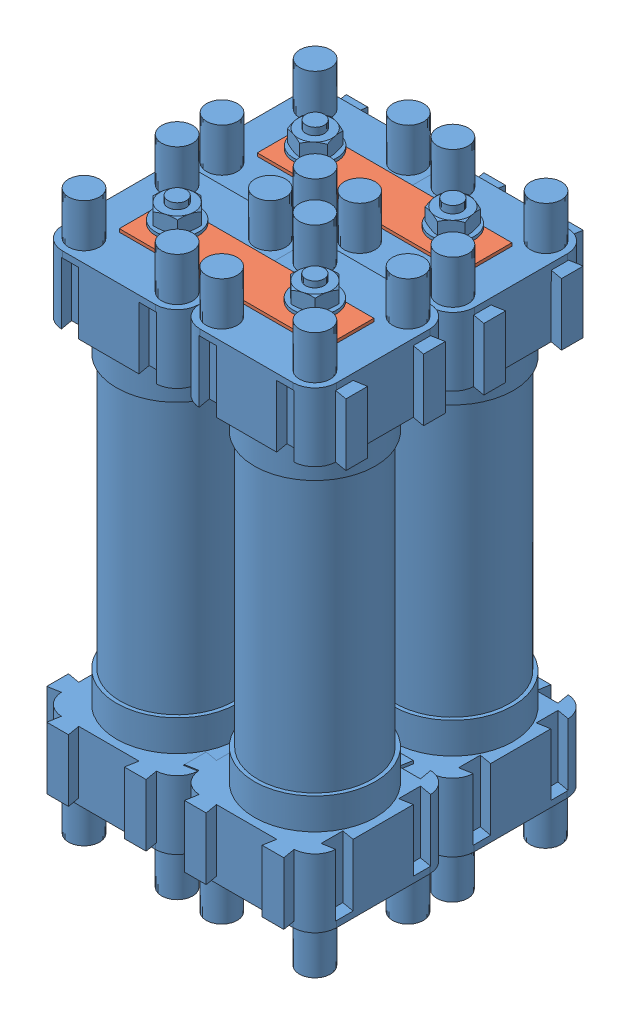
SolidWorks assembly Assem1, configuration Default. Lengths in mm.
Overall size (48.23 90.37 48.18).
7 component instances, 3 part files, 11 mates.
Components (placement in the parent):
- Cell w Caps-1: Cell w Caps [Default] at (52.4075 49.9991 53.4777) size (26 90 26)
- Cell w Caps-2: Cell w Caps [Default] at (74.4075 49.9991 53.2988) size (26 90 26)
- Cell w Caps-4: Cell w Caps [Default] at (74.5867 49.6475 31.2988) x (0 0 1) z (0.999999 -0.001067 0) size (26 90 26)
- Cell w Caps-6: Cell w Caps [Default] at (52.5866 49.6427 31.4777) x (0 0 1) z (0.999999 -0.001067 0) size (26 90 26)
- Cell link-1: Cell link [Default] at (63.4075 87.9991 53.2988) size (33 0.5 8)
- Cell link-2: Cell link [Default] at (63.6272 87.6593 31.2988) x (0.999999 -0.001067 0) z (0 0 1) size (33 0.5 8)
- Fused link-1: Fused link [Default] at (52.4501 11.6428 42.4773) x (-0.008726 0.000009 0.999962) z (0.999961 -0.001067 0.008726) size (33 1.5 8)
Mates (geometry in assembly coordinates):
- Coincident1: coincident: plane of Cell w Caps-1 through (65.4075 86.9991 53.4777) normal (1 0 0); plane of Cell w Caps-2 through (65.4075 86.9991 53.2988) normal (-1 0 0)
- Coincident2: coincident anti-aligned: plane of Cell w Caps-1 through (52.4075 86.9991 53.4777) normal (0 1 0); plane of Cell w Caps-2 through (74.4075 86.9991 53.2988) normal (0 -1 0)
- Coincident5: coincident anti-aligned: plane of Cell w Caps-2 through (74.4075 12.9991 44.2988) normal (0 0 -1); plane of Cell w Caps-4 through (74.5472 12.6476 44.2988) normal (0 0 1)
- Coincident8: coincident anti-aligned: plane of Cell w Caps-4 through (61.5472 12.6614 31.2988) normal (-0.999999 0.001067 0); plane of Cell w Caps-6 through (61.5472 12.6331 31.4777) normal (0.999999 -0.001067 0)
- Coincident9: coincident anti-aligned: plane of Cell w Caps-1 through (52.4075 12.9991 44.4777) normal (0 0 -1); plane of Cell w Caps-6 through (52.5472 12.6427 44.4777) normal (0 0 1)
- Coincident10: coincident anti-aligned: plane of Cell w Caps-2 through (74.4075 87.9991 53.2988) normal (0 1 0); plane of Cell link-1 through (63.4075 87.9991 53.2988) normal (0 -1 0)
- Concentric1: concentric anti-aligned: cylinder of Cell w Caps-2 through (74.4075 93.9991 53.2988) axis (0 -1 0) radius 1.5; circle of Cell link-1
- Coincident11: coincident anti-aligned: plane of Cell w Caps-4 through (74.6272 87.6475 31.2988) normal (0.001067 0.999999 0); plane of Cell link-2 through (63.6272 87.6593 31.2988) normal (-0.001067 -0.999999 0)
- Concentric2: concentric aligned: cylinder of Cell w Caps-4 through (74.6336 93.6475 31.2988) axis (-0.001067 -0.999999 0) radius 1.5; cylinder of Cell link-2 through (74.6277 88.1475 31.2988) axis (-0.001067 -0.999999 0) radius 2
- Coincident12: coincident anti-aligned: plane of Cell w Caps-6 through (52.5461 11.6427 31.4777) normal (-0.001067 -0.999999 0); plane of Fused link-1 through (61.4333 11.6333 38.1142) normal (0.001067 0.999999 0)
- Concentric4: concentric aligned: cylinder of Cell w Caps-6 through (52.5397 5.6427 31.4777) axis (0.001067 0.999999 0) radius 1.5; cylinder of Fused link-1 through (52.5456 11.1427 31.4777) axis (0.001067 0.999999 0) radius 2
